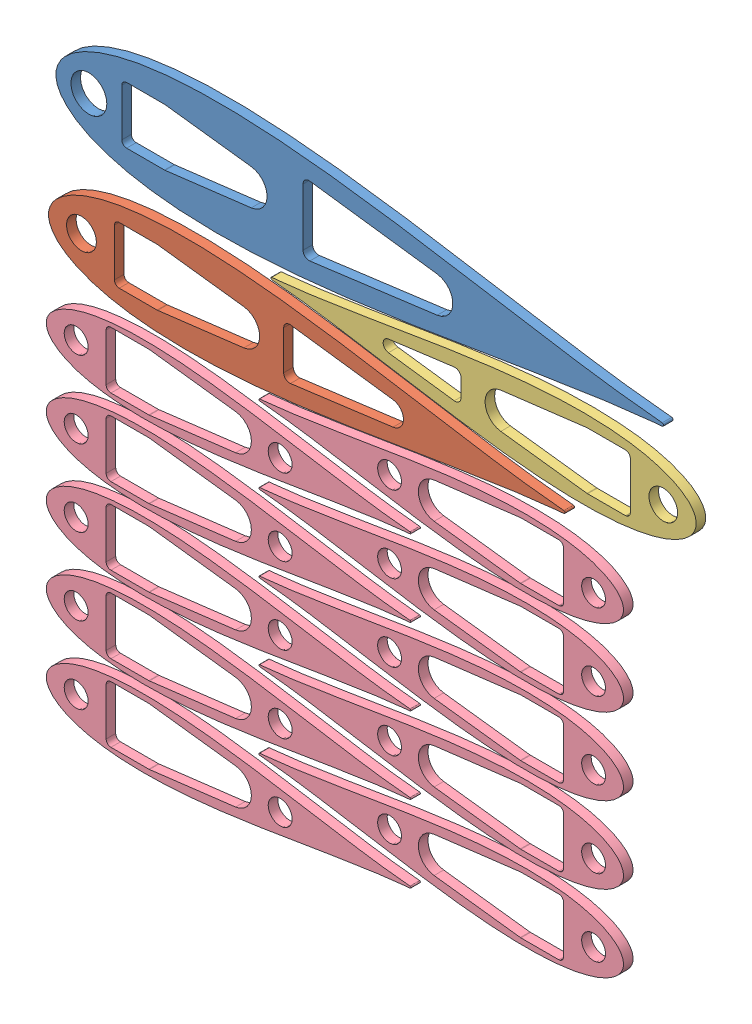
SolidWorks assembly Assem1, configuration Default. Lengths in mm.
Overall size (396.24 380.92 7.62).
14 component instances, 5 part files, 8 mates.
Components (placement in the parent):
- Keel_streamline_rib_wide_first-1: Keel_streamline_rib_wide_first [Lightening] at origin size (388.27 127.32 5.08)
- Keel_streamline_rib_wide_firstandahalf-1: Keel_streamline_rib_wide_firstandahalf [Lightening] at (-3.9237 -66.2142 0) size (330.03 108.22 5.08)
- Keel_streamline_rib_wide_second-1: Keel_streamline_rib_wide_second [Lightening] at (339.2724 -36.4571 0) x (-1 0 0) z (0 0 1) size (271.79 89.12 5.08)
- Keel_streamline_rib_wide-11: Keel_streamline_rib_wide [Lightening] at (298.2154 -97.8936 -2.54) x (-1 0 0) z (0 0 1) size (232.96 76.39 5.08)
- 18x24_Stock-1: 18x24_Stock [Default] at (291.1432 -187.782 0) x (0 0 -1) z (1 0 0) size (2.54 457.2 609.6) (hidden)
- Keel_streamline_rib_wide-15: Keel_streamline_rib_wide [Lightening] at (-5.1296 -116.5172 0) size (232.96 76.39 5.08)
- Keel_streamline_rib_wide-16: Keel_streamline_rib_wide [Lightening] at (-5.1296 -157.1572 0) size (232.96 76.39 5.08)
- Keel_streamline_rib_wide-17: Keel_streamline_rib_wide [Lightening] at (-5.1296 -197.7972 0) size (232.96 76.39 5.08)
- Keel_streamline_rib_wide-18: Keel_streamline_rib_wide [Lightening] at (-5.1296 -238.4372 0) size (232.96 76.39 5.08)
- Keel_streamline_rib_wide-19: Keel_streamline_rib_wide [Lightening] at (-5.1296 -279.0772 0) size (232.96 76.39 5.08)
- Keel_streamline_rib_wide-20: Keel_streamline_rib_wide [Lightening] at (298.2154 -138.5336 -2.54) x (-1 0 0) z (0 0 1) size (232.96 76.39 5.08)
- Keel_streamline_rib_wide-21: Keel_streamline_rib_wide [Lightening] at (298.2154 -179.1736 -2.54) x (-1 0 0) z (0 0 1) size (232.96 76.39 5.08)
- Keel_streamline_rib_wide-22: Keel_streamline_rib_wide [Lightening] at (298.2154 -219.8136 -2.54) x (-1 0 0) z (0 0 1) size (232.96 76.39 5.08)
- Keel_streamline_rib_wide-23: Keel_streamline_rib_wide [Lightening] at (298.2154 -260.4536 -2.54) x (-1 0 0) z (0 0 1) size (232.96 76.39 5.08)
Mates (geometry in assembly coordinates):
- Coincident1: coincident aligned: plane of Keel_streamline_rib_wide_first-1 through (0 0 5.08) normal (0 0 1); plane of Keel_streamline_rib_wide_firstandahalf-1 through (-3.9237 -66.2142 5.08) normal (0 0 1)
- Coincident2: coincident aligned: plane of Keel_streamline_rib_wide_first-1 through (0 0 5.08) normal (0 0 1); plane of Keel_streamline_rib_wide_second-1 through (339.2724 -36.4571 5.08) normal (0 0 1)
- Coincident3: coincident aligned: plane of Keel_streamline_rib_wide_first-1 through (0 0 5.08) normal (0 0 1); plane of ? through (163.8172 -7.2302 5.08) normal (0 0 1)
- Coincident4: coincident aligned: plane of ? through (163.8172 -7.2302 5.08) normal (0 0 1); plane of ? through (165.5549 -21.4024 5.08) normal (0 0 1)
- Coincident5: coincident aligned: plane of Keel_streamline_rib_wide_first-1 through (0 0 5.08) normal (0 0 1); plane of ? through (45.5848 -26.8085 5.08) normal (0 0 1)
- Coincident6: coincident aligned: plane of ? through (45.5848 -26.8085 5.08) normal (0 0 1); plane of ? through (56.2442 -32.5048 5.08) normal (0 0 1)
- Parallel1: parallel anti-aligned: plane of Keel_streamline_rib_wide_second-1 through (339.2724 -36.4571 0) normal (-1 0 0); plane of assembly through (0 0 0) normal (1 0 0)
- Coincident15: coincident anti-aligned: plane of Keel_streamline_rib_wide_first-1 through (0 0 0) normal (0 0 -1); plane of 18x24_Stock-1 through (291.1432 -187.782 0) normal (0 0 1)
